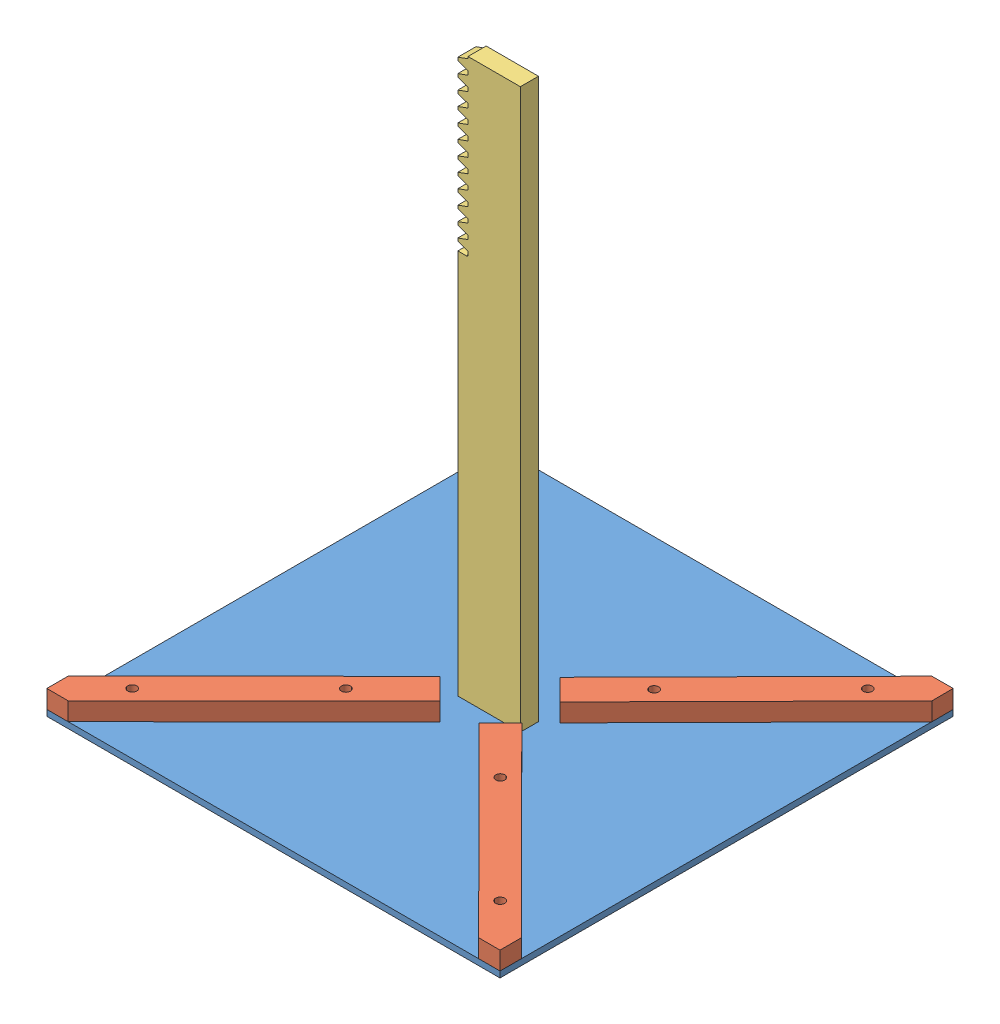
SolidWorks assembly Funny Action, configuration Défaut. Lengths in mm.
Overall size (157.12 190 157.06).
7 component instances, 4 part files, 11 mates.
Components (placement in the parent):
- Funny Action - Pièce1-1: Funny Action - Pièce1 [Défaut] at (4.7636 206.3668 -25.4997) size (150 2 150)
- Funny Action - Pièce2-1: Funny Action - Pièce2 [Défaut] at (-37.963 208.3668 -67.7213) x (0.701596 0 0.712575) z (0 1 0) size (92 10 6)
- Funny Action - Pièce2-2: Funny Action - Pièce2 [Défaut] at (47.4096 214.3668 -67.8008) x (-0.703347 0 0.710847) z (0 -1 0) size (92 10 6)
- Funny Action - Pièce2-3: Funny Action - Pièce2 [Défaut] at (-37.6788 214.3668 17.004) x (0.707773 0 -0.70644) z (0 -1 0) size (92 10 6)
- Funny Action - Pièce2-4: Funny Action - Pièce2 [Défaut] at (47.2731 214.3668 16.9369) x (-0.706314 0 -0.707898) z (0 -1 0) size (92 10 6)
- Cremaillere monté parasol-1: Cremaillere monté parasol [ISO - Rack-spur - rectangular 1.5M 20PA 6FW 20.2PH 185L---SAll] at (15.6599 393.3668 -28.3409) x (0 -1 0) z (0 0 -1) size (185 20.7 6)
- Funny Action - Cylindre 3mm-1: Funny Action - Cylindre 3mm [Défaut] at (4.7636 203.3668 -25.4997) size (30 3 30)
Mates (geometry in assembly coordinates):
- Coïncidente1: coincident anti-aligned: line of Funny Action - Pièce1-1 through (-70.2364 208.3668 -100.4997) axis (0 -1 0); line of Funny Action - Pièce2-1 through (-70.2364 208.3668 -100.4997) axis (0 1 0)
- Coïncidente3: coincident anti-aligned: plane of Funny Action - Pièce1-1 through (4.7636 208.3668 -25.4997) normal (0 1 0); plane of Funny Action - Pièce2-1 through (-37.963 208.3668 -67.7213) normal (0 -1 0)
- Coïncidente4: coincident anti-aligned: plane of Funny Action - Pièce1-1 through (4.7636 208.3668 -25.4997) normal (0 1 0); plane of Funny Action - Pièce2-2 through (47.4096 208.3668 -67.8008) normal (0 -1 0)
- Coïncidente5: coincident anti-aligned: plane of Funny Action - Pièce1-1 through (4.7636 208.3668 -25.4997) normal (0 1 0); plane of Funny Action - Pièce2-3 through (-37.6788 208.3668 17.004) normal (0 -1 0)
- Coïncidente6: coincident anti-aligned: plane of Funny Action - Pièce1-1 through (4.7636 208.3668 -25.4997) normal (0 1 0); plane of Funny Action - Pièce2-4 through (47.2731 208.3668 16.9369) normal (0 -1 0)
- Coïncidente7: coincident aligned: line of Funny Action - Pièce1-1 through (79.7636 208.3668 -100.4997) axis (0 -1 0); line of Funny Action - Pièce2-2 through (79.7636 214.3668 -100.4997) axis (0 -1 0)
- Coïncidente8: coincident aligned: line of Funny Action - Pièce1-1 through (-70.2364 208.3668 49.5003) axis (0 -1 0); line of Funny Action - Pièce2-3 through (-70.2364 214.3668 49.5003) axis (0 -1 0)
- Coïncidente9: coincident aligned: line of Funny Action - Pièce1-1 through (79.7636 208.3668 49.5003) axis (0 -1 0); line of Funny Action - Pièce2-4 through (79.7636 214.3668 49.5003) axis (0 -1 0)
- Coïncidente12: coincident anti-aligned: plane of Funny Action - Pièce1-1 through (4.7636 208.3668 -25.4997) normal (0 1 0); plane of Cremaillere monté parasol-1 through (15.6599 208.3668 -22.3409) normal (0 -1 0)
- Coïncidente13: coincident: plane of Funny Action - Pièce1-1 through (4.7636 206.3668 -25.4997) normal (0 -1 0); plane of Funny Action - Cylindre 3mm-1 through (4.7636 206.3668 -25.4997) normal (0 1 0)
- Coaxiale1: concentric aligned: circle of Funny Action - Pièce1-1; circle of Funny Action - Cylindre 3mm-1
